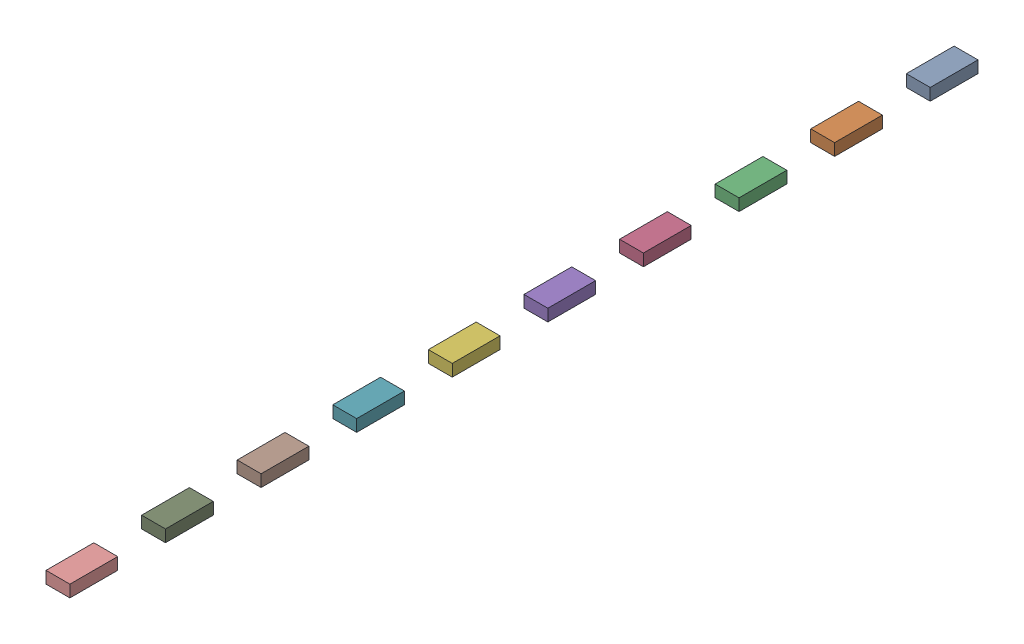
SolidWorks assembly lane_addetive, configuration Default. Lengths in mm.
Overall size (50 25 1900).
10 component instances, 1 part files, 0 mates.
Components (placement in the parent):
- lane-1: lane [Default] at (18.4792 -7.5587 32.8341) size (50 25 100)
- lane-2: lane [Default] at (18.4792 -7.5587 232.8341) size (50 25 100)
- lane-3: lane [Default] at (18.4792 -7.5587 432.8341) size (50 25 100)
- lane-4: lane [Default] at (18.4792 -7.5587 632.8341) size (50 25 100)
- lane-5: lane [Default] at (18.4792 -7.5587 832.8341) size (50 25 100)
- lane-6: lane [Default] at (18.4792 -7.5587 1032.8341) size (50 25 100)
- lane-7: lane [Default] at (18.4792 -7.5587 1232.8341) size (50 25 100)
- lane-8: lane [Default] at (18.4792 -7.5587 1432.8341) size (50 25 100)
- lane-9: lane [Default] at (18.4792 -7.5587 1632.8341) size (50 25 100)
- lane-10: lane [Default] at (18.4792 -7.5587 1832.8341) size (50 25 100)
